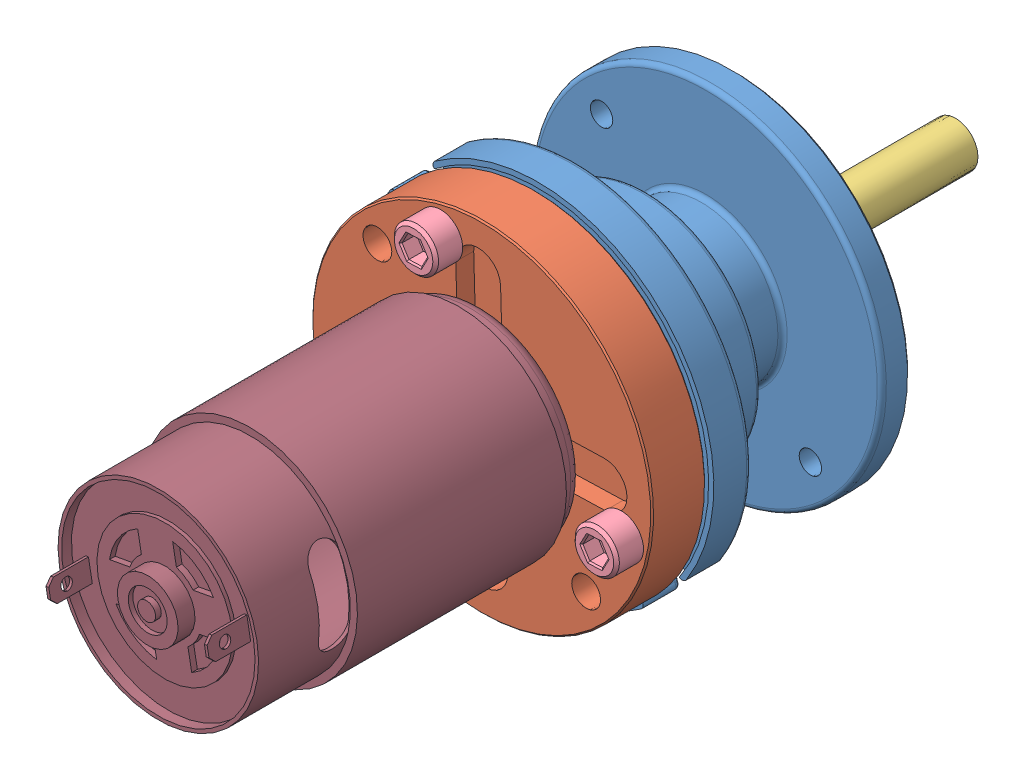
SolidWorks assembly FP trans, configuration Default. Lengths in mm.
Overall size (87.97 87.97 146.55).
26 component instances, 13 part files, 20 mates.
Components (placement in the parent):
- housing-1: housing [Default] at (0 0 -0.3607) x (0.727443 -0.686168 0) z (-0.686168 -0.727443 0) size (62.23 38.74 62.23)
- Universal_cap-1: Universal_cap [Default] at (0 0 44.4038) x (-0.686168 -0.727443 0) z (0.727443 -0.686168 0) size (60.32 9.53 60.32)
- shaft-1: shaft [Default] at (0 0 27.4116) x (0.976329 0.21629 0) z (0 0 1) size (28.57 28.57 260.35)
- 10-32x0625_shcs-1: 10-32x0625_shcs [Default] at (-17.4287 -18.477 49.179) x (-0.194995 0.980804 0) z (0.980804 0.194995 0) size (7.82 20.65 7.82)
- 10-32x0625_shcs-2: 10-32x0625_shcs [Default] at (24.7159 -5.8552 49.179) x (-0.884425 0.466682 0) z (0.466682 0.884425 0) size (7.82 20.65 7.82)
- 10-32x0625_shcs-3: 10-32x0625_shcs [Default] at (-7.2872 24.3322 49.179) x (-0.884425 0.466682 0) z (0.466682 0.884425 0) size (7.82 20.65 7.82)
- ring_gear-1: ring_gear [Default] at (-0.073 -0.0219 33.0553) x (-0.686168 -0.727443 0) z (0 0 1) size (43.01 38.1 7)
- sun_gear-1: sun_gear [Default] at (0 0 34.9416) x (0.294759 -0.955572 0) z (0 0 1) size (13.47 13.4 9.53)
- 90295A160_nylon_washer-1: 90295A160_nylon_washer [Default] at (0 0 21) x (-0.995317 0.096661 0) z (-0.096661 -0.995317 0) size (19.05 1.32 19.05)
- 90295A160_nylon_washer-2: 90295A160_nylon_washer [Default] at (0 0 8.6208) x (0.616153 -0.787627 0) z (-0.787627 -0.616153 0) size (19.05 1.32 19.05)
- 90295A160_nylon_washer-3: 90295A160_nylon_washer [Default] at (0 0 9.9416) x (0.658273 -0.752779 0) z (-0.752779 -0.658273 0) size (19.05 1.32 19.05)
- 90295A160_nylon_washer-4: 90295A160_nylon_washer [Default] at (0 0 11.2624) x (0.658273 -0.752779 0) z (-0.752779 -0.658273 0) size (19.05 1.32 19.05)
- 8mmx22mmx7mm_bearing-1: 8mmx22mmx7mm_bearing [Default] at (0 0 19.6792) x (-0.788017 -0.615654 0) z (0.615654 -0.788017 0) size (22 7 22)
- 8mmx19mmx6mm_bearing-1: 8mmx19mmx6mm_bearing [Default] at (0 0 2.6208) x (-0.978933 -0.204182 0) z (-0.204182 0.978933 0) size (19 6 19)
- planet_gear2-5: planet_gear2 [Default] at (-10.7982 -2.3922 27.7926) x (0.66792 0.744233 0) z (0 0 -1) size (11.11 11.11 7.11)
- shim010-1: shim010 [Default] at (0 0 34.5236) x (0.798455 -0.602055 0) z (-0.602055 -0.798455 0) size (25.4 0.25 25.4)
- planet_pin-5: planet_pin [Default] at (-10.7982 -2.3922 21.0616) x (0.999415 0.034186 0) z (0 0 1) size (3.17 3.17 12.7)
- planet_pin-6: planet_pin [Default] at (-1.0617 -11.0089 21.0616) x (0.276324 0.961065 0) z (0 0 1) size (3.17 3.17 12.7)
- planet_pin-7: planet_pin [Default] at (10.142 -4.4117 21.0616) x (-0.828638 0.559785 0) z (0 0 1) size (3.17 3.17 12.7)
- planet_pin-8: planet_pin [Default] at (7.3299 8.2823 21.0616) x (-0.78845 -0.615099 0) z (0 0 1) size (3.17 3.17 12.7)
- planet_pin-9: planet_pin [Default] at (-5.6119 9.5305 21.0616) x (0.341349 -0.939937 0) z (0 0 1) size (3.17 3.17 12.7)
- planet_gear2-6: planet_gear2 [Default] at (-1.0617 -11.0089 27.7926) x (-0.501409 0.865211 0) z (0 0 -1) size (11.11 11.11 7.11)
- planet_gear2-7: planet_gear2 [Default] at (10.142 -4.4117 27.7926) x (-0.977808 -0.209503 0) z (0 0 -1) size (11.11 11.11 7.11)
- planet_gear2-8: planet_gear2 [Default] at (7.3299 8.2823 27.7926) x (-0.10291 -0.994691 0) z (0 0 -1) size (11.11 11.11 7.11)
- planet_gear2-9: planet_gear2 [Default] at (-5.6119 9.5305 27.7926) x (0.914206 -0.40525 0) z (0 0 -1) size (11.11 11.11 7.11)
- FisherPriceMotor-1: FisherPriceMotor [Default] at (0 0 73.0288) x (0.983668 0.179993 0) z (0 0 -1) size (38 37.92 85.2)
Mates (geometry in assembly coordinates):
- Concentric1: concentric aligned: cylinder of planet_pin-5 through (-10.7982 -2.3922 33.7616) axis (0 0 -1) radius 1.5875; circle of shaft-1
- Coincident2: coincident aligned: circle of shaft-1; plane of planet_pin-5 through (-10.7982 -2.3922 21.0616) normal (0 0 -1)
- Concentric2: concentric aligned: circle of planet_gear2-5; cylinder of planet_pin-5 through (-10.7982 -2.3922 33.7616) axis (0 0 -1) radius 1.5875
- Coincident3: coincident anti-aligned: plane of shaft-1 through (0 0 27.4116) normal (0 0 1); plane of planet_gear2-5 through (-10.7982 -2.3922 27.4116) normal (0 0 -1)
- Concentric3: concentric aligned: cylinder of sun_gear-1 through (0 0 13.6859) axis (0 0 1) radius 1.5875; cylinder of shaft-1 through (0 0 -232.9384) axis (0 0 1) radius 4.7625
- Coincident4: coincident anti-aligned: plane of shaft-1 through (1.9527 0.4326 25.4116) normal (0 0 1); plane of sun_gear-1 through (0 0 25.4116) normal (0 0 -1)
- Concentric4: concentric aligned: circle of housing-1; cylinder of shaft-1 through (0 0 -232.9384) axis (0 0 1) radius 4.7625
- Concentric5: concentric aligned: cylinder of housing-1 through (0 0 -60.3607) axis (0 0 1) radius 13.5509; cylinder of 8mmx19mmx6mm_bearing-1 through (0 0 8.6208) axis (0 0 1) radius 9.5
- Coincident6: coincident anti-aligned: plane of housing-1 through (6.3236 -21.1144 26.0553) normal (0.230518 0.973068 0); plane of ring_gear-1 through (-15.1667 -16.0235 26.0553) normal (-0.230518 -0.973068 0)
- Coincident8: coincident anti-aligned: plane of housing-1 through (-15.1239 -16.0336 26.0553) normal (0 0 1); plane of ring_gear-1 through (-6.3839 21.0504 26.0553) normal (0 0 -1)
- Coincident9: coincident anti-aligned: plane of shim010-1 through (0 0 34.5236) normal (0 0 -1); plane of planet_gear2-6 through (-1.0617 -11.0089 34.5236) normal (0 0 1)
- Concentric6: concentric anti-aligned: cylinder of sun_gear-1 through (0 0 13.6859) axis (0 0 1) radius 1.5875; circle of shim010-1
- Concentric7: concentric anti-aligned: cylinder of housing-1 through (-7.2872 24.3322 33.1673) axis (0 0 1) radius 1.9837; cylinder of 10-32x0625_shcs-3 through (-7.2872 24.3322 28.5288) axis (0 0 -1) radius 2.3876
- Concentric8: concentric anti-aligned: cylinder of housing-1 through (-17.4287 -18.477 33.1673) axis (0 0 1) radius 1.9837; cylinder of 10-32x0625_shcs-1 through (-17.4287 -18.477 28.5288) axis (0 0 -1) radius 2.3876
- Concentric9: concentric anti-aligned: cylinder of housing-1 through (24.7159 -5.8552 33.1673) axis (0 0 1) radius 1.9837; cylinder of 10-32x0625_shcs-2 through (24.7159 -5.8552 28.5288) axis (0 0 -1) radius 2.3876
- Concentric10: concentric aligned: cylinder of Universal_cap-1 through (-7.2872 24.3322 39.9588) axis (0 0 -1) radius 2.5527; circle of 10-32x0625_shcs-3
- Concentric11: concentric anti-aligned: circle of Universal_cap-1; circle of 10-32x0625_shcs-1
- Concentric20: concentric aligned: cylinder of Universal_cap-1 through (0 0 -41.4387) axis (0 0 -1) radius 6.604; cylinder of FisherPriceMotor-1 through (0 0 44.4038) axis (0 0 -1) radius 6.5
- Coincident11: coincident anti-aligned: plane of Universal_cap-1 through (0 0 44.4038) normal (0 0 1); plane of FisherPriceMotor-1 through (0 0 44.4038) normal (0 0 -1)
- Cut-Extrude2: unknown = 38.1 mm: plane of housing-1 through (0 0 -4.2977) normal (0 0 -1)
